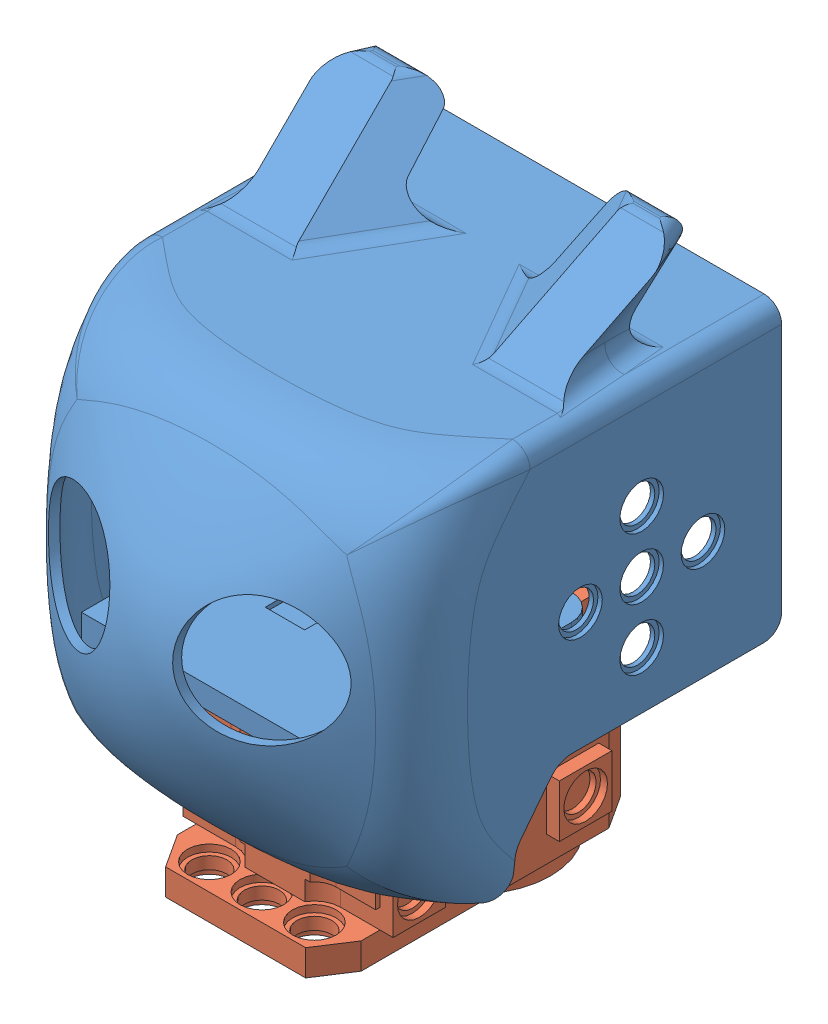
SolidWorks assembly headAsm, configuration Default. Lengths in mm.
Overall size (45.91 66.53 58.75).
2 component instances, 2 part files, 9 mates.
Components (placement in the parent):
- head-1: head [Default] at origin size (45.91 54.55 58.75)
- XL-1: XL [Default] at (0 -19.5 2.4049) x (1 0 0) z (0 -1 0) size (24 36 27)
Mates (geometry in assembly coordinates):
- Coincident1: coincident aligned: plane of head-1 through (0 0 0) normal (0 0 1)
- Coincident2: coincident aligned: plane of head-1 through (0 0 0) normal (0 1 0)
- Coincident3: coincident aligned: plane of head-1 through (0 0 0) normal (1 0 0)
- Coincident4: coordinate: point of head-1
- Coincident7: coincident aligned: plane of head-1 through (0 0 0) normal (1 0 0); plane of XL-1 through (0 -19.5 2.4049) normal (1 0 0)
- Parallel1: parallel anti-aligned: plane of head-1 through (0 0 0) normal (0 1 0); plane of XL-1 through (0 -19.5 2.4049) normal (0 -1 0)
- Coincident9: coincident anti-aligned: plane of head-1 through (-11.5 -7.5 -3.4834) normal (0 -1 0); plane of XL-1 through (0 -7.5 2.4049) normal (0 1 0)
- Coincident10: coincident anti-aligned: plane of head-1 through (-12 -8.25 12.0166) normal (1 0 0); plane of XL-1 through (-12 -19.5 2.4049) normal (-1 0 0)
- Tangent1: tangent anti-aligned: line of XL-1; face of XL-1
